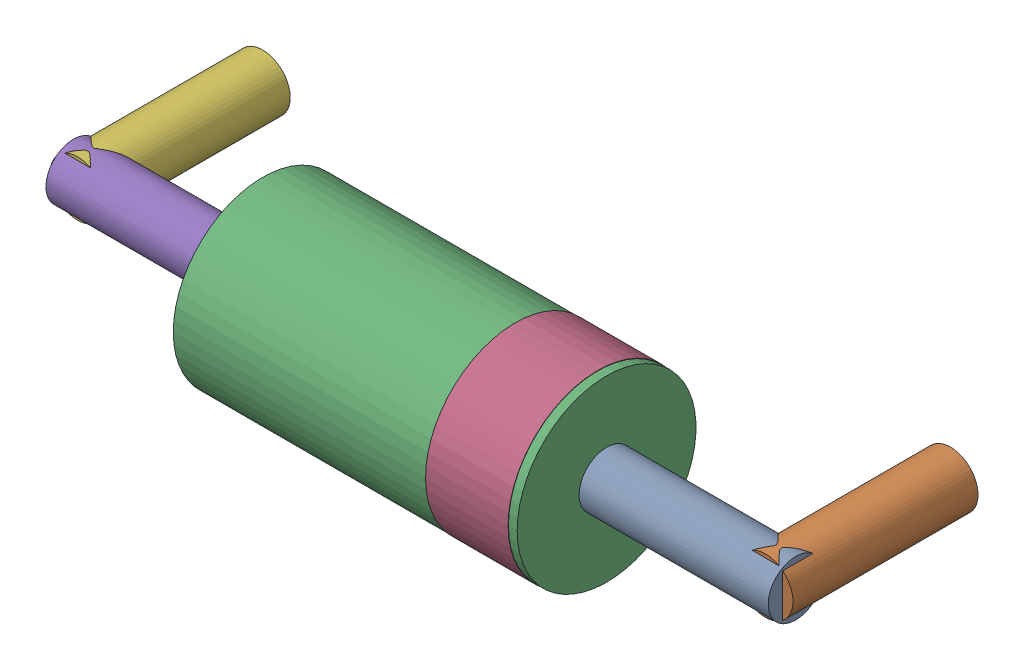
SolidWorks assembly D8, configuration Default. Lengths in mm.
Overall size (10.8 2.61 3.81).
12 component instances, 6 part files, 0 mates.
Components (placement in the parent):
- -1733042672-1: -1733042672 [Default] at (501.2503 282.9977 1.5) x (0 0 -1) z (-1 0 0) size (0.8 0.8 2.75)
  - Cylinder-1: Cylinder [Default] at origin size (0.8 0.8 2.75)
- -1733042992-1: -1733042992 [Default] at (500.9999 282.9999 -1) x (-1 0 0) z (0 0 1) size (0.8 0.8 2.69)
  - Cylinder_2-1: Cylinder_2 [Default] at origin size (0.8 0.8 2.69)
- -1733042432-1: -1733042432 [Default] at (498.5001 282.9975 1.5) x (0 0 -1) z (-1 0 0) size (2.6 2.6 5)
  - Cylinder_3-1: Cylinder_3 [Default] at origin size (2.6 2.6 5)
- -1733042152-1: -1733042152 [Default] at (498.3731 282.9976 1.5) x (0 0 -1) z (-1 0 0) size (2.61 2.61 1.2)
  - Cylinder_4-1: Cylinder_4 [Default] at origin size (2.61 2.61 1.2)
- -1733041072-1: -1733041072 [Default] at (490.7497 283.0023 1.5) x (0 0 -1) z (1 0 0) size (0.8 0.8 2.75)
  - Cylinder_5-1: Cylinder_5 [Default] at origin size (0.8 0.8 2.75)
- -1733041192-1: -1733041192 [Default] at (491.0001 283.0001 -1) x (1 0 0) z (0 0 1) size (0.8 0.8 2.69)
  - Cylinder_6-1: Cylinder_6 [Default] at origin size (0.8 0.8 2.69)
